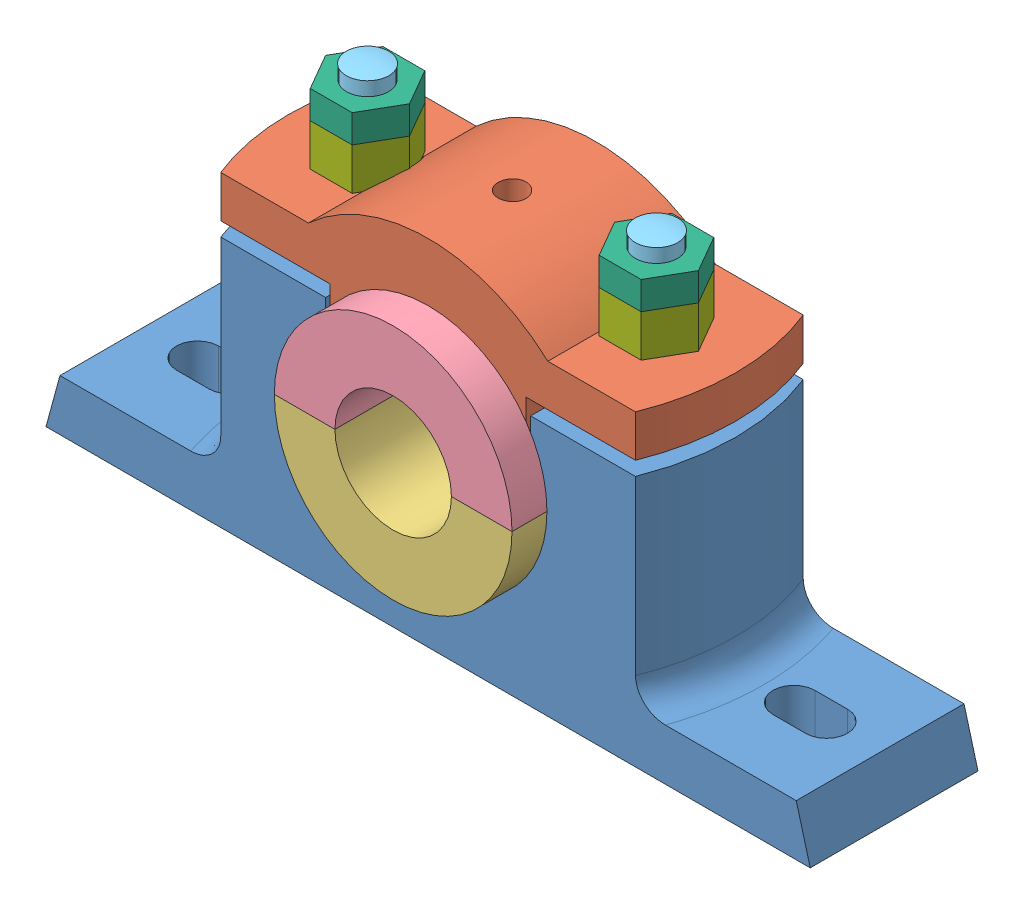
SolidWorks assembly Assem1, configuration Default. Lengths in mm.
Overall size (164 84.47 51).
10 component instances, 7 part files, 18 mates.
Components (placement in the parent):
- casting-1: casting [Default] at (68.7953 60.9546 120.2745) size (164 54 36)
- cap-1: cap [Default] at (68.7953 98.9546 120.2745) size (96 32 36)
- brass with excrude-1: brass with excrude [Default] at (68.7953 98.9546 120.2745) x (0 0 -1) z (0 -1 0) size (51 51 25.5)
- brass with holes-1: brass with holes [Default] at (68.7953 98.9546 120.2744) x (0 0 1) z (0 1 0) size (51 51 25.5)
- bolt1-1: bolt1 [Default] at (37.7953 68.9546 120.2745) x (1 0 0) z (0 -1 0) size (19 19 82.47)
- nut 9,6-1: nut 9,6 [Default] at (99.7953 141.9546 120.2745) x (1 0 0) z (0 -1 0) size (18 15.59 6)
- nut 9,9-1: nut 9,9 [Default] at (99.7953 135.9546 120.2745) x (1 0 0) z (0 -1 0) size (18 15.59 9)
- bolt1-2: bolt1 [Default] at (99.7953 68.9546 120.2745) x (1 0 0) z (0 -1 0) size (19 19 82.47)
- nut 9,9-2: nut 9,9 [Default] at (37.7953 135.9546 120.2745) x (1 0 0) z (0 -1 0) size (18 15.59 9)
- nut 9,6-2: nut 9,6 [Default] at (37.7953 141.9546 120.2745) x (1 0 0) z (0 -1 0) size (18 15.59 6)
Mates (geometry in assembly coordinates):
- Concentric1: concentric aligned: cylinder of casting-1 through (68.7953 79.9546 120.2745) axis (0 1 0) radius 3; cylinder of brass with excrude-1 through (68.7953 98.9556 120.2745) axis (0 1 0) radius 3
- Concentric3: concentric anti-aligned: cylinder of casting-1 through (68.7953 98.9546 138.2745) axis (0 0 -1) radius 19; cylinder of brass with excrude-1 through (68.7953 98.9546 120.2745) axis (0 0 1) radius 17.5
- Concentric4: concentric anti-aligned: cylinder of brass with excrude-1 through (68.7953 98.9546 120.2745) axis (0 0 1) radius 12.5; cylinder of brass with holes-1 through (68.7953 98.9546 94.7744) axis (0 0 -1) radius 12.4999
- Concentric5: concentric anti-aligned: cylinder of brass with excrude-1 through (68.7953 98.9546 120.2745) axis (0 0 1) radius 12.5; cylinder of brass with holes-1 through (68.7953 98.9546 94.7744) axis (0 0 -1) radius 12.4999
- Coincident2: coincident aligned: plane of brass with excrude-1 through (56.2953 98.9546 145.7745) normal (0 0 1); plane of brass with holes-1 through (68.7953 98.9546 145.7745) normal (0 0 1)
- Concentric12: concentric aligned: cylinder of cap-1 through (68.7953 98.9546 138.2745) axis (0 0 -1) radius 19; cylinder of brass with holes-1 through (68.7953 98.9546 94.7744) axis (0 0 -1) radius 17.5001
- Concentric14: concentric aligned: cylinder of casting-1 through (37.7953 114.9546 120.2745) axis (0 1 0) radius 4.5; cylinder of cap-1 through (37.7953 126.9546 120.2745) axis (0 1 0) radius 4.5
- Coincident7: coincident anti-aligned: plane of casting-1 through (68.7953 68.9546 120.2745) normal (0 -1 0); plane of bolt1-1 through (37.7953 68.9546 120.2745) normal (0 1 0)
- Concentric15: concentric anti-aligned: cylinder of casting-1 through (37.7953 114.9546 120.2745) axis (0 1 0) radius 4.5; cylinder of bolt1-1 through (37.7953 144.9546 120.2745) axis (0 -1 0) radius 4.5
- Coincident8: coincident anti-aligned: plane of casting-1 through (68.7953 68.9546 120.2745) normal (0 -1 0); plane of bolt1-2 through (99.7953 68.9546 120.2745) normal (0 1 0)
- Concentric17: concentric anti-aligned: cylinder of casting-1 through (99.7953 114.9546 120.2745) axis (0 1 0) radius 4.5; cylinder of bolt1-2 through (99.7953 144.9546 120.2745) axis (0 -1 0) radius 4.5
- Coincident9: coincident anti-aligned: plane of cap-1 through (118.7953 126.9546 138.2745) normal (0 1 0); plane of nut 9,9-1 through (99.7953 126.9546 120.2745) normal (0 -1 0)
- Concentric18: concentric anti-aligned: cylinder of nut 9,9-1 through (99.7953 126.9546 120.2745) axis (0 1 0) radius 4.5; cylinder of bolt1-2 through (99.7953 144.9546 120.2745) axis (0 -1 0) radius 4.5
- Coincident10: coincident anti-aligned: plane of nut 9,6-1 through (99.7953 135.9546 120.2745) normal (0 -1 0); plane of nut 9,9-1 through (99.7953 135.9546 120.2745) normal (0 1 0)
- Concentric19: concentric anti-aligned: cylinder of nut 9,6-1 through (99.7953 135.9546 120.2745) axis (0 1 0) radius 4.5; cylinder of bolt1-2 through (99.7953 144.9546 120.2745) axis (0 -1 0) radius 4.5
- Coincident12: coincident anti-aligned: plane of cap-1 through (18.7953 126.9546 138.2745) normal (0 1 0); plane of nut 9,9-2 through (37.7953 126.9546 120.2745) normal (0 -1 0)
- Concentric21: concentric anti-aligned: cylinder of bolt1-1 through (37.7953 144.9546 120.2745) axis (0 -1 0) radius 4.5; cylinder of nut 9,6-2 through (37.7953 135.9546 120.2745) axis (0 1 0) radius 4.5
- Coincident13: coincident anti-aligned: plane of nut 9,9-2 through (37.7953 135.9546 120.2745) normal (0 1 0); plane of nut 9,6-2 through (37.7953 135.9546 120.2745) normal (0 -1 0)
